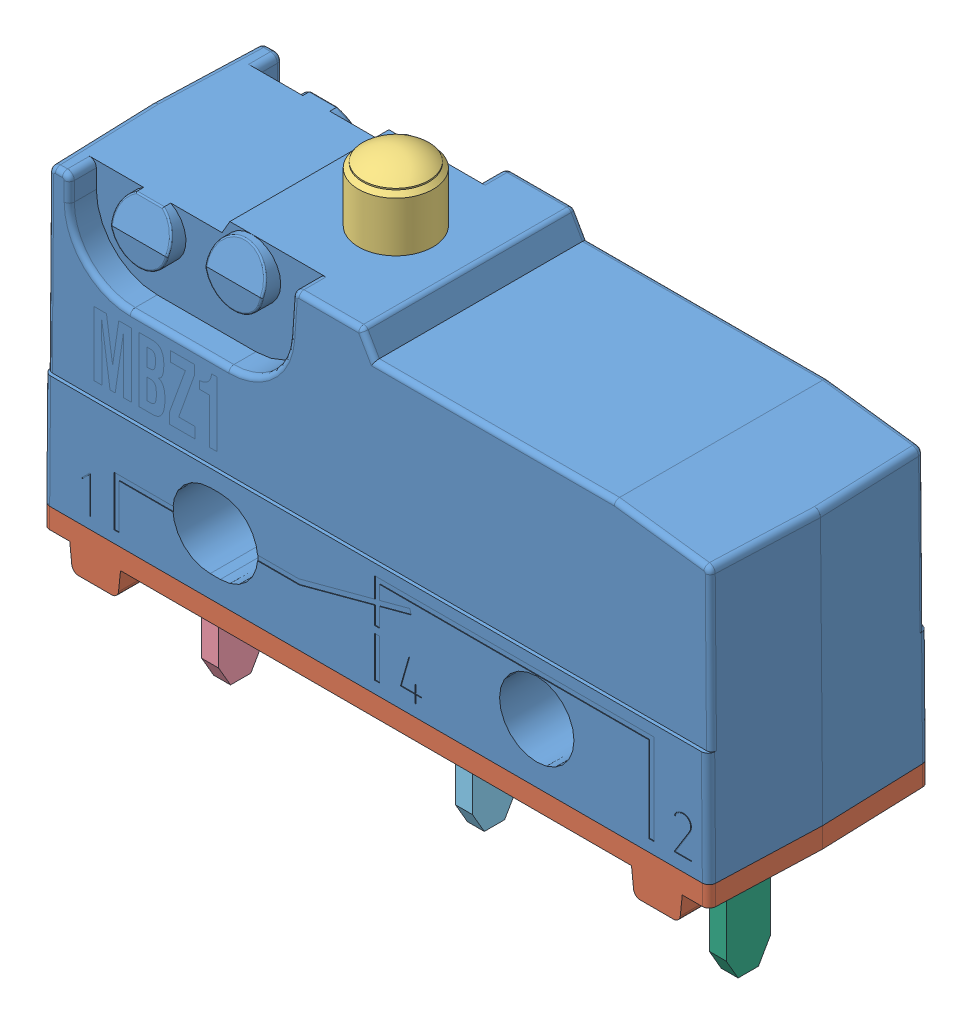
SolidWorks assembly MBZ1_xxxC02X02, configuration Default. Lengths in mm.
Overall size (19.9 15.9 6.5).
7 component instances, 6 part files, 0 mates.
Components (placement in the parent):
- MBZ1_xxxC02X02.stp-1: MBZ1_xxxC02X02.stp [Default] at origin size (19.9 15.9 6.5)
  - D_Kappe_MBZ1.stp-1: D_Kappe_MBZ1.stp [Default] at origin size (19.9 9.06 6.5)
  - D_Sockel_m_Abstandshalter_MBZ1.stp-1: D_Sockel_m_Abstandshalter_MBZ1.stp [Default] at (0 -0.6 3.25) size (19.9 1.35 6.5)
  - D_Bet_X_E4tiger mit Kugelform_MBZ1.stp-1: D_Bet_X_E4tiger mit Kugelform_MBZ1.stp [Default] at (7.285 9.05 3.25) x (-1 0 0) z (0 0 -1) size (2.2 2 2.2)
  - D_Leiterplattenanschluss_0.5x1.3_links_MBZ1.stp-1: D_Leiterplattenanschluss_0.5x1.3_links_MBZ1.stp [Default] at (2.45 -0.6 4.65) x (0 0 -1) z (1 0 0) size (2.8 4.25 0.5)
  - D_Leiterplattenanschluss_0.5x1.3_mitte_MBZ1.stp-1: D_Leiterplattenanschluss_0.5x1.3_mitte_MBZ1.stp [Default] at (9.95 -0.6 4.65) x (0 0 -1) z (1 0 0) size (2.8 4.25 0.5)
  - D_Leiterplattenanschluss_0.5x1.3_rechts_MBZ1.stp-1: D_Leiterplattenanschluss_0.5x1.3_rechts_MBZ1.stp [Default] at (17.45 -0.6 4.65) x (0 0 -1) z (1 0 0) size (2.8 4.25 0.5)
